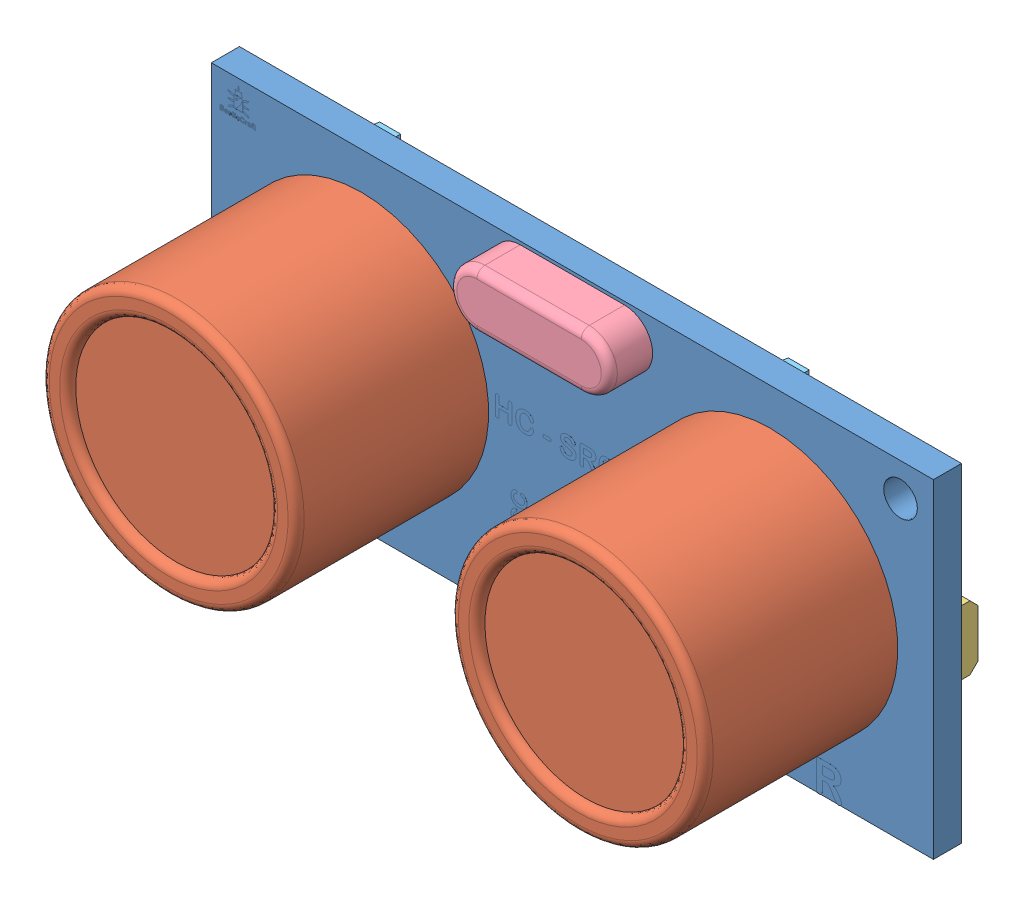
SolidWorks assembly HC-SR04, configuration Default. Lengths in mm.
Overall size (45 20.53 19.69).
47 component instances, 8 part files, 2 mates.
Components (placement in the parent):
- HC-SR04_HC-SR04 Ping Sensor-1: HC-SR04_HC-SR04 Ping Sensor [Default] at (22.5 10.25 -1.75) x (0 -1 0) z (0 0 1) size (20.53 45 15.35)
  - HC-SR04_PCB-1: HC-SR04_PCB [Default] at origin size (20.53 45 1.75)
  - HC-SR04_Transducer-1: HC-SR04_Transducer [Default] at (0 -13.16 13.25) x (1 0 0) z (0 -1 0) size (15.88 12 15.88)
  - HC-SR04_Transducer-2: HC-SR04_Transducer [Default] at (0 12.34 13.25) x (1 0 0) z (0 -1 0) size (15.88 12 15.88)
  - HC-SR04_14 Pin SMT-1: HC-SR04_14 Pin SMT [Default] at (0 17.5274 -0.85) x (1 0 0) z (0 1 0) size (6 1.6 8.8)
  - HC-SR04_14 Pin SMT-2: HC-SR04_14 Pin SMT [Default] at (-0.35 -18.5 -0.85) x (0 -1 0) z (1 0 0) size (6 1.6 8.8)
  - HC-SR04_14 Pin SMT-3: HC-SR04_14 Pin SMT [Default] at (0 -0.3826 -0.85) x (1 0 0) z (0 1 0) size (6 1.6 8.8)
  - HC-SR04_HC-SR04 Crystal-1: HC-SR04_HC-SR04 Crystal [Default] at (-8.3 0 1.75) x (0 -1 0) z (0 0 1) size (10 3.5 2.7)
  - HC-SR04_ssot3-1: HC-SR04_ssot3 [Default] at (-7.9706 11.2297 0) x (1 0 0) z (0 1 0) size (3 1.13 3.09)
  - HC-SR04_ssot3-2: HC-SR04_ssot3 [Default] at (-7.9706 -14.2327 0) x (1 0 0) z (0 1 0) size (3 1.13 3.09)
  - HC-SR04_MLC0603-1: HC-SR04_MLC0603 [Default] at (1.5086 11.2209 0) x (1 0 0) z (0 1 0) size (2.36 0.6 1.03)
  - HC-SR04_MLC0603-2: HC-SR04_MLC0603 [Default] at (-4.7079 -6.8438 0) x (1 0 0) z (0 1 0) size (2.36 0.6 1.03)
  - HC-SR04_MLC0603-3: HC-SR04_MLC0603 [Default] at (-8.4554 -9.9341 0) x (0 1 0) z (-1 0 0) size (2.36 0.6 1.03)
  - HC-SR04_MLC0603-4: HC-SR04_MLC0603 [Default] at (7.7901 17.1702 0) x (1 0 0) z (0 1 0) size (2.36 0.6 1.03)
  - HC-SR04_MLC0603-5: HC-SR04_MLC0603 [Default] at (-4.2399 7.0151 0) x (0 1 0) z (-1 0 0) size (2.36 0.6 1.03)
  - HC-SR04_MLC0603-6: HC-SR04_MLC0603 [Default] at (-8.2266 4.8481 0) x (1 0 0) z (0 1 0) size (2.36 0.6 1.03)
  - HC-SR04_MLC0603-7: HC-SR04_MLC0603 [Default] at (-8.276 3.0726 0) x (1 0 0) z (0 1 0) size (2.36 0.6 1.03)
  - HC-SR04_MLC0603-8: HC-SR04_MLC0603 [Default] at (-8.1718 18.0917 0) x (1 0 0) z (0 1 0) size (2.36 0.6 1.03)
  - HC-SR04_MLC0603-9: HC-SR04_MLC0603 [Default] at (-5.0505 19.9858 0) x (0 1 0) z (-1 0 0) size (2.36 0.6 1.03)
  - HC-SR04_MLC0603-10: HC-SR04_MLC0603 [Default] at (4.9221 -0.625 0) x (0 1 0) z (-1 0 0) size (2.36 0.6 1.03)
  - HC-SR04_MLC0603-11: HC-SR04_MLC0603 [Default] at (-6.3425 7.0242 0) x (0 1 0) z (-1 0 0) size (2.36 0.6 1.03)
  - HC-SR04_MLC0603-12: HC-SR04_MLC0603 [Default] at (4.867 -3.8906 0) x (0 1 0) z (-1 0 0) size (2.36 0.6 1.03)
  - HC-SR04_MLC0603-13: HC-SR04_MLC0603 [Default] at (7.7433 15.7761 0) x (1 0 0) z (0 1 0) size (2.36 0.6 1.03)
  - HC-SR04_MLC0603-14: HC-SR04_MLC0603 [Default] at (0.771 7.4861 0) x (0 1 0) z (-1 0 0) size (2.36 0.6 1.03)
  - HC-SR04_MLC0603-15: HC-SR04_MLC0603 [Default] at (-5.1303 17.0114 0) x (0 1 0) z (-1 0 0) size (2.36 0.6 1.03)
  - HC-SR04_MLC0603-16: HC-SR04_MLC0603 [Default] at (-8.2323 14.696 0) x (1 0 0) z (0 1 0) size (2.36 0.6 1.03)
  - HC-SR04_MLC0603-17: HC-SR04_MLC0603 [Default] at (7.5824 9.9685 0) x (1 0 0) z (0 1 0) size (2.36 0.6 1.03)
  - HC-SR04_MLC0603-18: HC-SR04_MLC0603 [Default] at (-8.2128 13.4796 0) x (1 0 0) z (0 1 0) size (2.36 0.6 1.03)
  - HC-SR04_MLC0603-19: HC-SR04_MLC0603 [Default] at (-5.1791 14.6881 0) x (1 0 0) z (0 1 0) size (2.36 0.6 1.03)
  - HC-SR04_MLC0603-20: HC-SR04_MLC0603 [Default] at (-2.0926 7.3723 0) x (1 0 0) z (0 1 0) size (2.36 0.6 1.03)
  - HC-SR04_603 cap on pad-1: HC-SR04_603 cap on pad [Default] at (-1.0221 -11.2109 0) x (0 1 0) z (-1 0 0) size (2.76 0.9 1.12)
  - HC-SR04_603 cap on pad-2: HC-SR04_603 cap on pad [Default] at (-8.0142 0.0287 0) x (1 0 0) z (0 1 0) size (2.76 0.9 1.12)
  - HC-SR04_603 cap on pad-3: HC-SR04_603 cap on pad [Default] at (-1.0582 -6.7842 0) x (1 0 0) z (0 1 0) size (2.76 0.9 1.12)
  - HC-SR04_603 cap on pad-4: HC-SR04_603 cap on pad [Default] at (8.2921 12.7142 0) x (0 1 0) z (-1 0 0) size (2.76 0.9 1.12)
  - HC-SR04_603 cap on pad-5: HC-SR04_603 cap on pad [Default] at (-2.0106 11.2331 0) x (1 0 0) z (0 1 0) size (2.76 0.9 1.12)
  - HC-SR04_603 cap on pad-6: HC-SR04_603 cap on pad [Default] at (4.491 7.5361 0) x (0 1 0) z (-1 0 0) size (2.76 0.9 1.12)
  - HC-SR04_603 cap on pad-7: HC-SR04_603 cap on pad [Default] at (-7.8611 -20.9225 0) x (1 0 0) z (0 1 0) size (2.76 0.9 1.12)
  - HC-SR04_603 cap on pad-8: HC-SR04_603 cap on pad [Default] at (-7.8553 -18.6213 0) x (1 0 0) z (0 1 0) size (2.76 0.9 1.12)
  - HC-SR04_603 cap on pad-9: HC-SR04_603 cap on pad [Default] at (2.5708 7.5761 0) x (0 1 0) z (-1 0 0) size (2.76 0.9 1.12)
  - HC-SR04_603 cap on pad-10: HC-SR04_603 cap on pad [Default] at (5.7718 -17.5016 0) x (0 1 0) z (-1 0 0) size (2.76 0.9 1.12)
  - HC-SR04_603 cap on pad-11: HC-SR04_603 cap on pad [Default] at (-8.071 -5.768 0) x (1 0 0) z (0 1 0) size (2.76 0.9 1.12)
  - HC-SR04_603 cap on pad-12: HC-SR04_603 cap on pad [Default] at (7.8006 20.8278 0) x (1 0 0) z (0 1 0) size (2.76 0.9 1.12)
  - HC-SR04_603 cap on pad-13: HC-SR04_603 cap on pad [Default] at (-8.1408 16.1462 0) x (1 0 0) z (0 1 0) size (2.76 0.9 1.12)
  - HC-SR04_603 cap on pad-14: HC-SR04_603 cap on pad [Default] at (7.8006 18.9728 0) x (1 0 0) z (0 1 0) size (2.76 0.9 1.12)
  - HC-SR04_603 cap on pad-15: HC-SR04_603 cap on pad [Default] at (-2.0811 9.4105 0) x (1 0 0) z (0 1 0) size (2.76 0.9 1.12)
  - HC-SR04_603 cap on pad-16: HC-SR04_603 cap on pad [Default] at (0.9766 -11.2109 0) x (0 1 0) z (-1 0 0) size (2.76 0.9 1.12)
- Header Vertical 2_54mm Pitch2-14 Way-1: Header Vertical 2_54mm Pitch2-14 Way [4 Way] at (19.9998 2.8881 -1.75) x (0 -1 0) z (1 0 0) size (2.54 8.88 10.16)
Mates (geometry in assembly coordinates):
- Coincident1: coincident: plane of HC-SR04_HC-SR04 Ping Sensor-1/HC-SR04_PCB-1 through (0 20.5 -1.75) normal (0 0 -1); plane of Header Vertical 2_54mm Pitch2-14 Way-1 through (26.3498 3.8581 -1.75) normal (0 0 1)
- Lock1: lock: unknown of HC-SR04_HC-SR04 Ping Sensor-1/HC-SR04_PCB-1; unknown of Header Vertical 2_54mm Pitch2-14 Way-1
